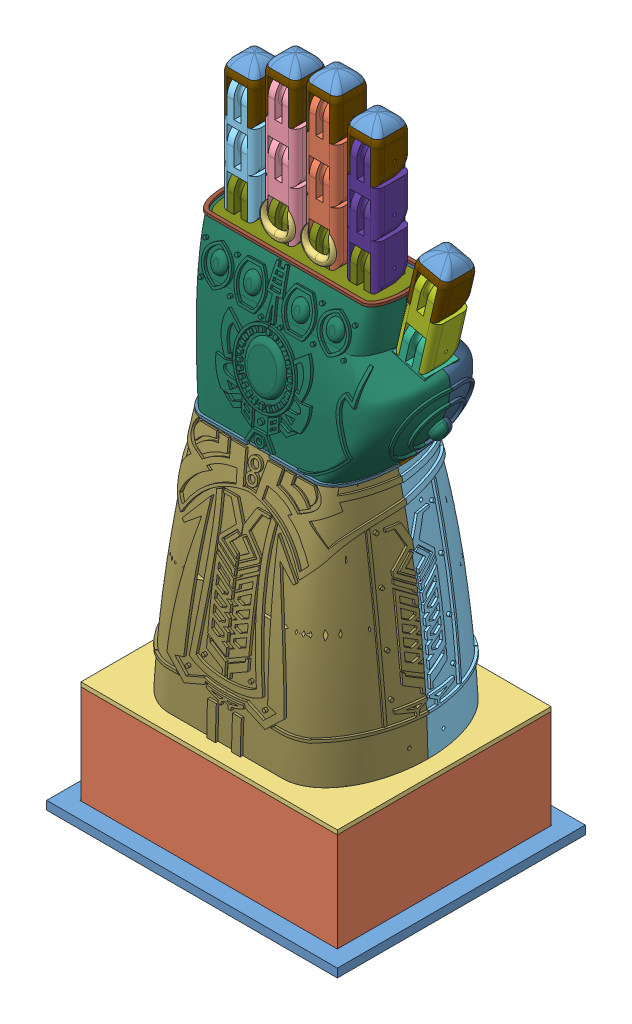
SolidWorks assembly Whole Assembly (Arduino), configuration Default. Lengths in mm.
Overall size (172.28 388 145).
55 component instances, 25 part files, 3 mates.
Components (placement in the parent):
- Base Assembly Arduino-1: Base Assembly Arduino [Default] at (-5.6156 -32.6258 -1.3231) size (170 85.37 145)
  - Base Bottom Arduino-2: Base Bottom Arduino [Default] at (57.5585 73.6731 141.2736) x (-1 0 0) z (0 0 -1) size (170 26.5 145)
  - Base Middle Arduino-1: Base Middle Arduino [Default] at (57.5585 76.1731 141.2736) size (150 60 125)
  - Base Top Arduino-1: Base Top Arduino [Default] at (57.5585 138.6731 141.2736) x (-1 0 0) z (0 0 -1) size (150 142.51 125)
  - Perfboard-1: Perfboard [Default] at (92.5585 96.1731 171.5736) x (0 0 -1) z (1 0 0) size (90 1.5 70)
- Hand Assembly-1: Hand Assembly [Default] at (13.6717 85.8928 -59.6122) size (158.09 323.06 115.63)
  - Back Assembly-1: Back Assembly [Default] at (44.8523 -8.137 52.37) size (148.72 230.56 93.41)
    - Arm Back-1: Arm Back [Default] at (-6.5809 28.2915 147.1931) size (139.6 140.5 63.13)
    - Servo Assembly-1: Servo Assembly [Default] at (-41.7016 175.9089 84.6263) x (1 0 0) z (0 -1 0) size (86 65.5 122.79)
      - Bed-1: Bed [Default] at (2.1207 32.6668 137.6174) size (66 39.5 122)
      - S3003-2: S3003 [Default] at (35.1207 44.6668 109.6174) x (0 0 -1) z (1 0 0) size (56.04 47.8 36.5)
      - S3003-3: S3003 [Default] at (13.1207 41.1668 109.6174) x (0 0 1) z (-1 0 0) size (56.04 47.8 36.5)
      - S3003-4: S3003 [Default] at (57.1207 41.1668 109.6174) x (0 0 1) z (-1 0 0) size (56.04 47.8 36.5)
      - S3003-5: S3003 [Default] at (13.1207 35.6668 43.6174) x (0 0 1) z (-1 0 0) size (56.04 47.8 36.5)
      - S3003-6: S3003 [Default] at (57.1207 35.6668 43.6174) x (0 0 1) z (-1 0 0) size (56.04 47.8 36.5)
      - String holder-2: String holder [Default] at (2.1207 60.1668 75.3674) x (1 0 0) z (0 -1 0) size (86 2.5 50)
    - Hand Bottom Decoration Back-1: Hand Bottom Decoration Back [Default] at (-6.5809 168.2915 147.1931) size (104.1 1.5 40.1)
    - Hand Back-1: Hand Back [Default] at (-6.5809 169.7915 147.1931) size (139.36 90.89 40.4)
    - Hand Top Decoration-1: Hand Top Decoration [Default] at (-6.5809 257.2915 147.1931) size (110.31 1.5 21.89)
  - Front Assembly-1: Front Assembly [Default] at (65.248 14.3274 327.8682) x (-1 0 0) z (0 0 -1) size (150.75 230.56 96.01)
    - Arm Front-1: Arm Front [Default] at (26.9766 5.8272 128.3051) size (139.6 140.48 96.01)
    - Arm Upper Lid-1: Arm Upper Lid [Default] at (26.9766 5.8272 128.3051) size (97.03 2.56 56.64)
    - Hand Bottom Decoration Front-1: Hand Bottom Decoration Front [Default] at (26.9766 145.8272 128.3051) size (104.1 1.5 40.1)
    - Hand Front-1: Hand Front [Default] at (26.9766 147.3272 128.3051) x (-1 0 0) z (0 0 -1) size (139.35 90.89 52.36)
    - Hand Top Decoration-1: Hand Top Decoration [Default] at (26.9766 234.8272 128.3051) size (110.31 1.5 21.89)
  - Finger and Lid Assembly-1: Finger and Lid Assembly [Default] at (3.2326 208.2275 112.941) size (104.96 97.49 36.85)
    - Hand Lid-1: Hand Lid [Default] at (35.0387 -46.573 86.622) size (104.96 23.49 36.85)
    - Finger Assembly 2-1: Finger Assembly 2 [Default] at (62.9609 39.05 43.1895) size (20 84 20)
      - Finger Body 2-1: Finger Body 2 [Default] at (8.0779 21.877 43.4324) size (20 47 20)
      - Finger Body 2-2: Finger Body 2 [Default] at (8.0779 48.877 43.4324) size (20 47 20)
      - Finger Top-1: Finger Top [Default] at (8.0779 75.877 43.4324) size (20 24 20)
      - Finger Tip-1: Finger Tip [Default] at (8.0779 75.877 43.4324) size (18.77 6 18.77)
    - Finger Assembly 3-1: Finger Assembly 3 [Default] at (38.9609 39.05 43.1895) size (20 94 23.03)
      - Finger Body 3-1: Finger Body 3 [Default] at (8.0779 21.877 43.4324) size (20 52 20)
      - Finger Body 3-2: Finger Body 3 [Default] at (8.0779 53.877 43.4324) size (20 52 20)
      - Finger Top-1: Finger Top [Default] at (8.0779 85.877 43.4324) size (20 24 20)
      - Finger Tip-1: Finger Tip [Default] at (8.0779 85.877 43.4324) size (18.77 6 18.77)
      - Finger Moon-1: Finger Moon [Default] at (8.0779 11.877 53.4324) x (1 0 0) z (0 -1 0) size (20 3.57 18.53)
    - Finger Assembly 4-1: Finger Assembly 4 [Default] at (14.9609 39.05 43.1895) size (20 90 23.03)
      - Finger Body 4-1: Finger Body 4 [Default] at (8.0779 21.877 43.4324) size (20 50 20)
      - Finger Body 4-2: Finger Body 4 [Default] at (8.0779 51.877 43.4324) size (20 50 20)
      - Finger Top-1: Finger Top [Default] at (8.0779 81.877 43.4324) size (20 24 20)
      - Finger Tip-1: Finger Tip [Default] at (8.0779 81.877 43.4324) size (18.77 6 18.77)
      - Finger Moon-1: Finger Moon [Default] at (8.0779 11.877 53.4324) x (1 0 0) z (0 -1 0) size (20 3.57 18.53)
    - Finger Assembly 5-1: Finger Assembly 5 [Default] at (-9.0391 39.05 43.1895) size (20 78 20)
      - Finger Body 5-1: Finger Body 5 [Default] at (8.0779 21.877 43.4324) size (20 44 20)
      - Finger Body 5-2: Finger Body 5 [Default] at (8.0779 45.877 43.4324) size (20 44 20)
      - Finger Top-1: Finger Top [Default] at (8.0779 69.877 43.4324) size (20 24 20)
      - Finger Tip-1: Finger Tip [Default] at (8.0779 69.877 43.4324) size (18.77 6 18.77)
  - Thumb and Lid Assembly-1: Thumb and Lid Assembly [Default] at (91.1371 218.4921 182.3169) x (0.974839 -0.222909 0) z (0 0 1) size (20 65 20)
    - Thumb Joint-1: Thumb Joint [Default] at (-0.2704 3.0981 27.2461) size (20 25 20)
    - Finger Assembly 1-1: Finger Assembly 1 [Default] at (1.6517 -23.7789 -26.1863) size (20 60 20)
      - Finger Body 1-2: Finger Body 1 [Default] at (8.0779 51.877 43.4324) size (20 50 20)
      - Finger Top-1: Finger Top [Default] at (8.0779 81.877 43.4324) size (20 24 20)
      - Finger Tip-1: Finger Tip [Default] at (8.0779 81.877 43.4324) size (18.77 6 18.77)
Mates (geometry in assembly coordinates):
- Coincident1: coincident anti-aligned: plane of Base Assembly Arduino-1/Base Top Arduino-1 through (51.9429 106.0473 139.9504) normal (0 1 0); plane of Hand Assembly-1/Front Assembly-1/Arm Front-1 through (84.9431 106.0473 139.9508) normal (0 -1 0)
- Coincident2: coincident aligned: line of Base Assembly Arduino-1/Base Top Arduino-1 through (18.9429 106.0473 189.9504) axis (1 0 0); line of Hand Assembly-1/Front Assembly-1/Arm Front-1 through (18.9431 106.0473 189.9508) axis (1 0 0)
- Coincident3: coincident: point of assembly; face of Base Assembly Arduino-1/Base Top Arduino-1; point of Hand Assembly-1/Back Assembly-1/Arm Back-1
